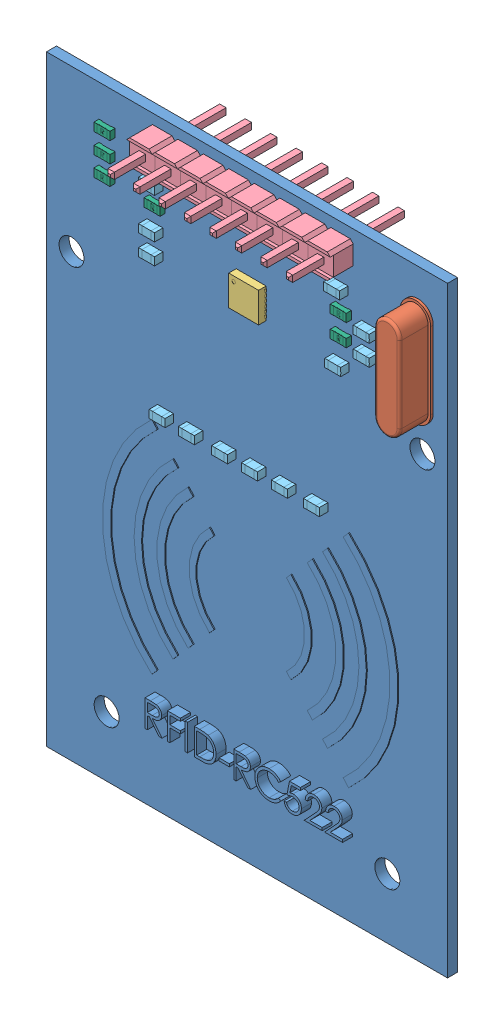
SolidWorks assembly RFID, configuration Default. Lengths in mm.
Overall size (40 60 11.54).
23 component instances, 6 part files, 0 mates.
Components (placement in the parent):
- Part1_1-1: Part1_1 [Default] at (-16.3439 30.7712 59.45) size (40 60 2)
- Part10-1: Part10 [Default] at (20.709 20.1029 60.45) x (0 1 0) z (0 0 1) size (10.67 3.05 5.63)
- User Library-S-PWSON-N12-1: User Library-S-PWSON-N12 [Default] at (4.1233 20.047 60.45) x (1 0 0) z (0 -1 0) size (3 0.8 3)
- User Library-Header_Male_8Pin-1: User Library-Header_Male_8Pin [Default] at (12.9823 28.5305 62.74) x (-1 0 0) z (0 0 -1) size (20.32 2.49 11.54)
- User Library-SMD Ceramic Capacitors_0603 (1608)_CH-1: User Library-SMD Ceramic Capacitors_0603 (1608)_CH [Default] at (-3.9959 5.9247 60.9127) size (1.72 0.91 0.98)
- User Library-SMD Ceramic Capacitors_0603 (1608)_CH-2: User Library-SMD Ceramic Capacitors_0603 (1608)_CH [Default] at (-1.0806 5.9034 60.9127) size (1.72 0.91 0.98)
- User Library-SMD Ceramic Capacitors_0603 (1608)_CH-3: User Library-SMD Ceramic Capacitors_0603 (1608)_CH [Default] at (2.2282 5.9089 60.9127) size (1.72 0.91 0.98)
- User Library-SMD Ceramic Capacitors_0603 (1608)_CH-4: User Library-SMD Ceramic Capacitors_0603 (1608)_CH [Default] at (5.214 5.921 60.9127) size (1.72 0.91 0.98)
- User Library-SMD Ceramic Capacitors_0603 (1608)_CH-5: User Library-SMD Ceramic Capacitors_0603 (1608)_CH [Default] at (8.193 5.9188 60.9127) size (1.72 0.91 0.98)
- User Library-SMD Ceramic Capacitors_0603 (1608)_CH-6: User Library-SMD Ceramic Capacitors_0603 (1608)_CH [Default] at (11.3855 5.9271 60.9127) size (1.72 0.91 0.98)
- User Library-SMD Ceramic Capacitors_0603 (1608)_CH-7: User Library-SMD Ceramic Capacitors_0603 (1608)_CH [Default] at (16.3593 23.3789 60.9127) size (1.72 0.91 0.98)
- User Library-SMD Ceramic Capacitors_0603 (1608)_CH-8: User Library-SMD Ceramic Capacitors_0603 (1608)_CH [Default] at (16.3593 21.3117 60.9127) size (1.72 0.91 0.98)
- User Library-SMD Ceramic Capacitors_0603 (1608)_CH-9: User Library-SMD Ceramic Capacitors_0603 (1608)_CH [Default] at (13.4136 25.6528 60.9127) size (1.72 0.91 0.98)
- User Library-SMD Ceramic Capacitors_0603 (1608)_CH-10: User Library-SMD Ceramic Capacitors_0603 (1608)_CH [Default] at (13.517 19.0895 60.9127) size (1.72 0.91 0.98)
- Part8-1: Part8 [Default] at (13.517 23.4826 60.704) size (1.6 0.81 0.51)
- Part8-2: Part8 [Default] at (13.517 21.3121 60.704) size (1.6 0.81 0.51)
- User Library-SMD Ceramic Capacitors_0603 (1608)_CH-11: User Library-SMD Ceramic Capacitors_0603 (1608)_CH [Default] at (-5.0547 25.4542 60.9127) size (1.72 0.91 0.98)
- User Library-SMD Ceramic Capacitors_0603 (1608)_CH-12: User Library-SMD Ceramic Capacitors_0603 (1608)_CH [Default] at (-5.0547 21.4355 60.9127) size (1.72 0.91 0.98)
- User Library-SMD Ceramic Capacitors_0603 (1608)_CH-13: User Library-SMD Ceramic Capacitors_0603 (1608)_CH [Default] at (-5.0547 19.367 60.9127) size (1.72 0.91 0.98)
- Part8-3: Part8 [Default] at (-5.0547 23.3861 60.704) size (1.6 0.81 0.51)
- Part8-4: Part8 [Default] at (-10.0418 25.4159 60.704) size (1.6 0.81 0.51)
- Part8-5: Part8 [Default] at (-10.0625 23.4569 60.704) size (1.6 0.81 0.51)
- Part8-6: Part8 [Default] at (-10.0541 27.4204 60.704) size (1.6 0.81 0.51)
